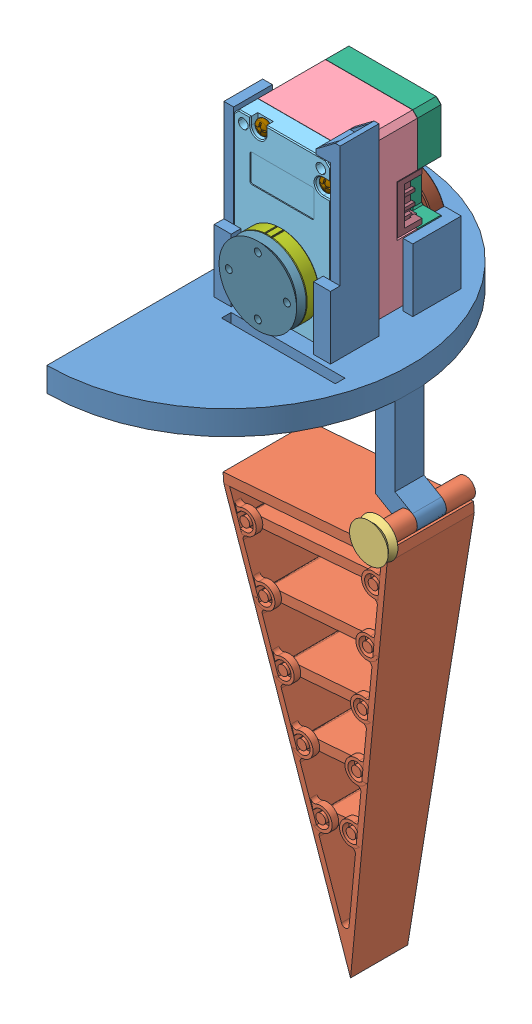
SolidWorks assembly ThumbMechanismAndFinger, configuration Default. Lengths in mm.
Overall size (48.5 149.11 75).
22 component instances, 14 part files, 8 mates.
Components (placement in the parent):
- ThumbMechanism-1: ThumbMechanism [Default] at (-1.3342 -6.4954 5.1169) size (42 65 75)
  - basePlateThumb-1: basePlateThumb [Standard] at (-58.1575 22.9574 -27.7146) size (42 65 75)
- FinGripperThumbPlate-1: FinGripperThumbPlate [Standard] at (-28.3819 -88.3371 23.9023) x (0.996987 0.07757 0) z (0 0 -1) size (34.35 85.85 18)
- Pulley-1: Pulley [Default] at (-19.4916 -3.538 23.9023) size (8 8 20)
- XL-330-1: XL-330 [Standard] at (-42.4246 30.962 17.4023) x (-1 0 0) z (0 0 1) size (20 34 29.02)
  - XL-330.stp-1: XL-330.stp [Standard] at origin size (20 34 29.02)
    - DC15_A01_CASE_M_DUMMY.stp-1: DC15_A01_CASE_M_DUMMY.stp [Standard] at origin size (20 34 18.5)
    - DC15_A01_CASE_F_DUMMY.stp-1: DC15_A01_CASE_F_DUMMY.stp [Standard] at origin size (20 34 4)
    - DC15_A01_CASE_B_DUMMY.stp-1: DC15_A01_CASE_B_DUMMY.stp [Standard] at (0 0 -19.5) size (20 34 7.6)
    - DC15_A01_HORN_DUMMY.stp-1: DC15_A01_HORN_DUMMY.stp [Standard] at (0 0 3.6) x (-1 0 0) z (0 1 0) size (16 5.62 16.01)
    - DC15_A01_LED_CAP2_DUMMY.stp-1: DC15_A01_LED_CAP2_DUMMY.stp [Standard] at (0 7.5 -17.6) x (-1 0 0) z (0 0 -1) size (5 2 4.5)
    - PHS_1_7X20_5_DC10.stp-1: PHS_1_7X20_5_DC10.stp [Standard] at (8.4 4.5 2) x (-1 0 0) z (0 1 0) size (3 21.77 3)
    - PHS_1_7X20_5_DC10.stp-2: PHS_1_7X20_5_DC10.stp [Standard] at (-8.4 4.5 2) x (-1 0 0) z (0 1 0) size (3 21.77 3)
    - PHS_1_7X20_5_DC10.stp-3: PHS_1_7X20_5_DC10.stp [Standard] at (4.9 -22.9 2) x (-1 0 0) z (0 1 0) size (3 21.77 3)
    - PHS_1_7X20_5_DC10.stp-4: PHS_1_7X20_5_DC10.stp [Standard] at (-8.4 -19.4 2) x (-1 0 0) z (0 1 0) size (3 21.77 3)
    - BTS2_M2_6X8.stp-1: BTS2_M2_6X8.stp [Standard] at (0 0 4.9) x (-1 0 0) z (0 1 0) size (5.5 9.57 5.5)
    - DC15_A01_HORN_IDLE2_DUMMY.stp-1: DC15_A01_HORN_IDLE2_DUMMY.stp [Standard] at (0 0 -19.6) x (1 0 0) z (0 0 -1) size (16 16 4.15)
    - DC15_A01_IDLE_CAP_DUMMY.stp-1: DC15_A01_IDLE_CAP_DUMMY.stp [Standard] at (0 0 -22.3) x (1 0 0) z (0 1 0) size (6.8 4.6 6.8)
    - BTS2_M2_6X8.stp-2: BTS2_M2_6X8.stp [Standard] at (0 0 -20.7) x (1 0 0) z (0 1 0) size (5.5 9.57 5.5)
    - B3B-EH.stp-1: B3B-EH.stp [Standard] at (7.7 -9 -10.4) x (0 -1 0) z (1 0 0) size (10 9.2 3.8)
    - B3B-EH.stp-2: B3B-EH.stp [Standard] at (-7.7 -9 -10.4) x (0 1 0) z (-1 0 0) size (10 9.2 3.8)
- Pulley_Motor-1: Pulley_Motor [Default] at (-42.4246 30.962 23.9023) size (16 16 2)
Mates (geometry in assembly coordinates):
- Coincident1: coincident aligned: circle of ThumbMechanism-1/basePlateThumb-1; circle of FinGripperThumbPlate-1
- Coincident2: coincident aligned: circle of FinGripperThumbPlate-1; circle of Pulley-1
- Coincident3: coincident anti-aligned: plane of Pulley-1 through (-19.4916 -3.538 23.9023) normal (0 0 -1); plane of XL-330-1/XL-330.stp-1/DC15_A01_HORN_DUMMY.stp-1 through (-42.4246 30.962 23.9023) normal (0 0 1)
- Coincident5: coincident anti-aligned: plane of ThumbMechanism-1/basePlateThumb-1 through (-59.4916 21.462 14.9023) normal (0 1 0); plane of XL-330-1/XL-330.stp-1/DC15_A01_CASE_M_DUMMY.stp-1 through (-52.4246 21.462 17.4023) normal (0 -1 0)
- Coincident6: coincident anti-aligned: plane of XL-330-1/XL-330.stp-1/DC15_A01_HORN_DUMMY.stp-1 through (-42.4246 30.962 23.9023) normal (0 0 1); plane of Pulley_Motor-1 through (-42.4246 30.962 23.9023) normal (0 0 -1)
- Concentric1: concentric anti-aligned: circle of XL-330-1/XL-330.stp-1/DC15_A01_HORN_DUMMY.stp-1; circle of Pulley_Motor-1
- Concentric2: concentric anti-aligned: circle of XL-330-1/XL-330.stp-1/DC15_A01_HORN_DUMMY.stp-1; circle of Pulley_Motor-1
- Coincident7: coincident anti-aligned: plane of ThumbMechanism-1/basePlateThumb-1 through (-32.4246 34.462 12.9023) normal (-1 0 0); plane of XL-330-1/XL-330.stp-1/DC15_A01_CASE_M_DUMMY.stp-1 through (-32.4246 21.462 17.4023) normal (1 0 0)
